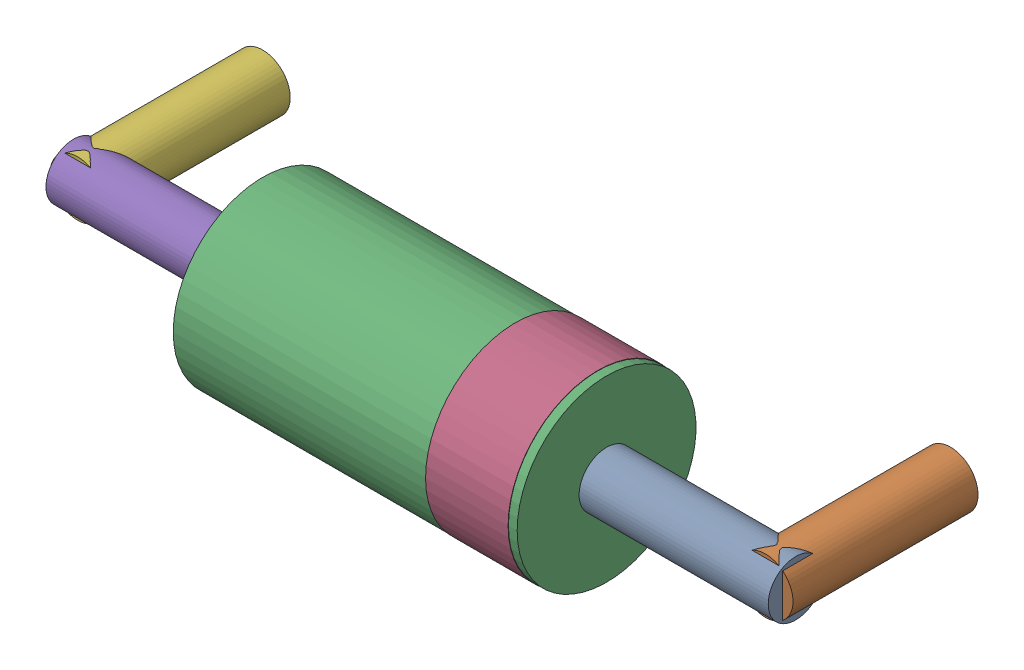
SolidWorks assembly D1_1, configuration Default. Lengths in mm.
Overall size (10.8 2.61 3.81).
12 component instances, 6 part files, 0 mates.
Components (placement in the parent):
- 1658496016-1: 1658496016 [Default] at (514.1494 293.1651 1.5) x (0 0 -1) z (-1 0 0) size (0.8 0.8 2.75)
  - Cylinder-1: Cylinder [Default] at origin size (0.8 0.8 2.75)
- 1658499696-1: 1658499696 [Default] at (513.8991 293.1673 -1) x (-1 0 0) z (0 0 1) size (0.8 0.8 2.69)
  - Cylinder_2-1: Cylinder_2 [Default] at origin size (0.8 0.8 2.69)
- 1658504056-1: 1658504056 [Default] at (511.3992 293.1649 1.5) x (0 0 -1) z (-1 0 0) size (2.6 2.6 5)
  - Cylinder_3-1: Cylinder_3 [Default] at origin size (2.6 2.6 5)
- 1658497416-1: 1658497416 [Default] at (511.2722 293.1649 1.5) x (0 0 -1) z (-1 0 0) size (2.61 2.61 1.2)
  - Cylinder_4-1: Cylinder_4 [Default] at origin size (2.61 2.61 1.2)
- 1658500936-1: 1658500936 [Default] at (503.6489 293.1697 1.5) x (0 0 -1) z (1 0 0) size (0.8 0.8 2.75)
  - Cylinder_5-1: Cylinder_5 [Default] at origin size (0.8 0.8 2.75)
- 1658496296-1: 1658496296 [Default] at (503.8992 293.1675 -1) x (1 0 0) z (0 0 1) size (0.8 0.8 2.69)
  - Cylinder_6-1: Cylinder_6 [Default] at origin size (0.8 0.8 2.69)
